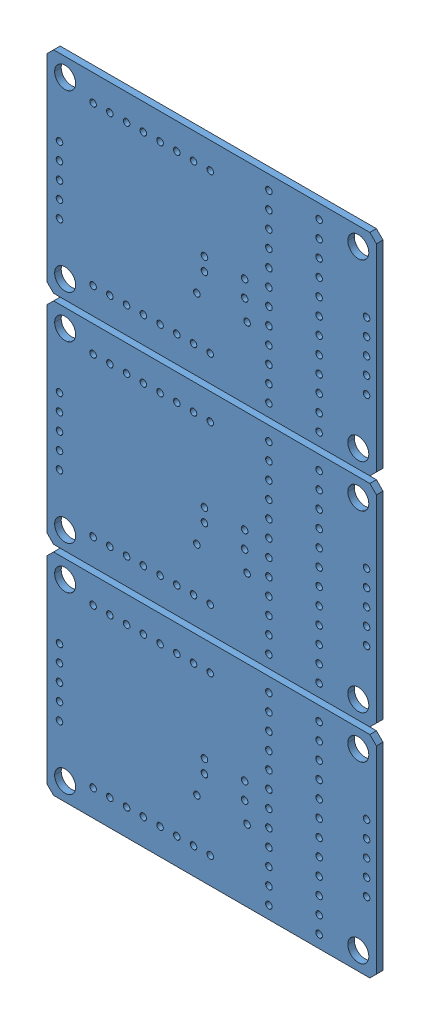
SolidWorks assembly Montagem4, configuration Valor predeterminado. Lengths in mm.
Overall size (50 98 1).
3 component instances, 1 part files, 6 mates.
Components (placement in the parent):
- PCB_LED-1: PCB_LED [Valor predeterminado] at origin size (50 32 1)
- PCB_LED-2: PCB_LED [Valor predeterminado] at (0 -33 0) size (50 32 1)
- PCB_LED-3: PCB_LED [Valor predeterminado] at (0 33 0) size (50 32 1)
Mates (geometry in assembly coordinates):
- Distância1: distance = 1 mm: plane of assembly; plane of assembly; plane of PCB_LED-2 through (25 -17 1) normal (0 1 0); plane of PCB_LED-1 through (25 -16 1) normal (0 -1 0)
- Distância3: distance = 1 mm: point of assembly; point of assembly; point of PCB_LED-1; point of PCB_LED-2
- Distância4: distance = 1 mm: point of assembly; point of assembly; point of PCB_LED-2; point of PCB_LED-1
- Distância5: distance = 1 mm: plane of assembly; plane of assembly; plane of PCB_LED-3 through (25 17 1) normal (0 -1 0); plane of PCB_LED-1 through (25 16 1) normal (0 1 0)
- Distância6: distance = 1 mm: point of assembly; point of assembly; point of PCB_LED-3; point of PCB_LED-1
- Distância7: distance = 1 mm: point of assembly; point of assembly; point of PCB_LED-1; point of PCB_LED-3
